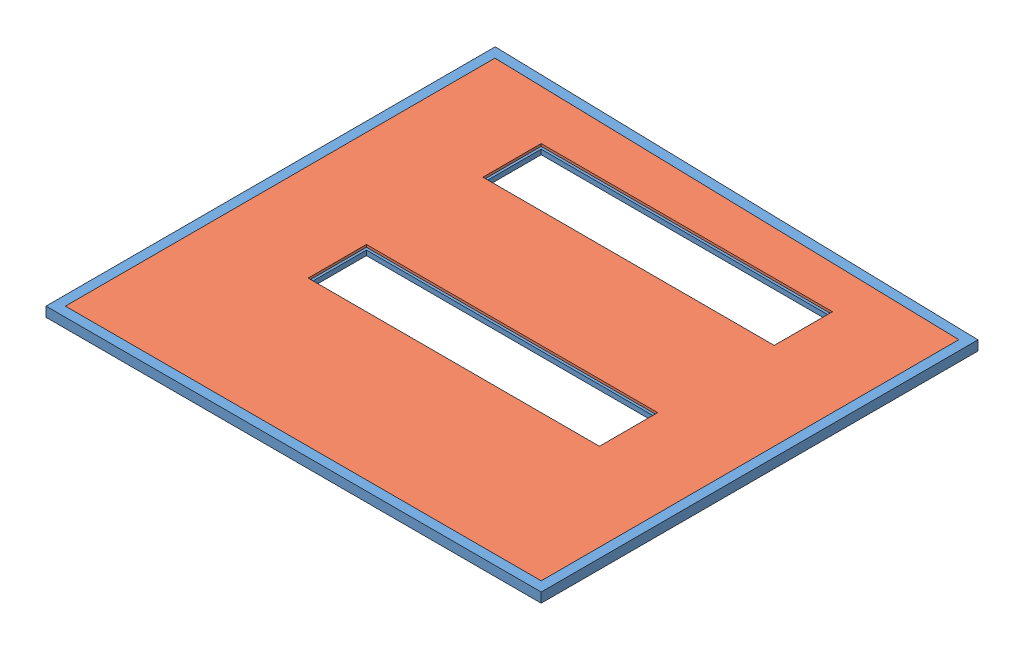
SolidWorks assembly LS_WALL_ASSEMBLY, configuration Default. Lengths in mm.
Overall size (2597.15 57.15 2381.89).
2 component instances, 2 part files, 3 mates.
Components (placement in the parent):
- LS_WALL FRAME_100.38-1: LS_WALL FRAME_100.38 [Default] at (-1380.2718 1545.4483 3677.4348) size (2597.15 57.15 2381.89)
- LS WALL_INSULATION-1: LS WALL_INSULATION [Default] at (-109.9336 1520.0483 2528.7711) x (0 0 1) z (-1 0 0) size (2247.14 50.8 2489.2)
Mates (geometry in assembly coordinates):
- Coincident1: coincident anti-aligned: plane of LS_WALL FRAME_100.38-1 through (1134.3282 1570.8483 1414.8845) normal (-1 0 0); plane of LS WALL_INSULATION-1 through (1134.3282 1570.8483 1466.8728) normal (1 0 0)
- Coincident2: coincident anti-aligned: plane of LS_WALL FRAME_100.38-1 through (1187.7682 1570.8483 3652.0348) normal (0 0 -1); plane of LS WALL_INSULATION-1 through (1134.3282 1570.8483 3652.0348) normal (0 0 1)
- Coincident3: coincident aligned: plane of LS_WALL FRAME_100.38-1 through (1187.7682 1570.8483 3702.8348) normal (0 1 0); plane of LS WALL_INSULATION-1 through (-109.9336 1570.8483 2528.7711) normal (0 1 0)
